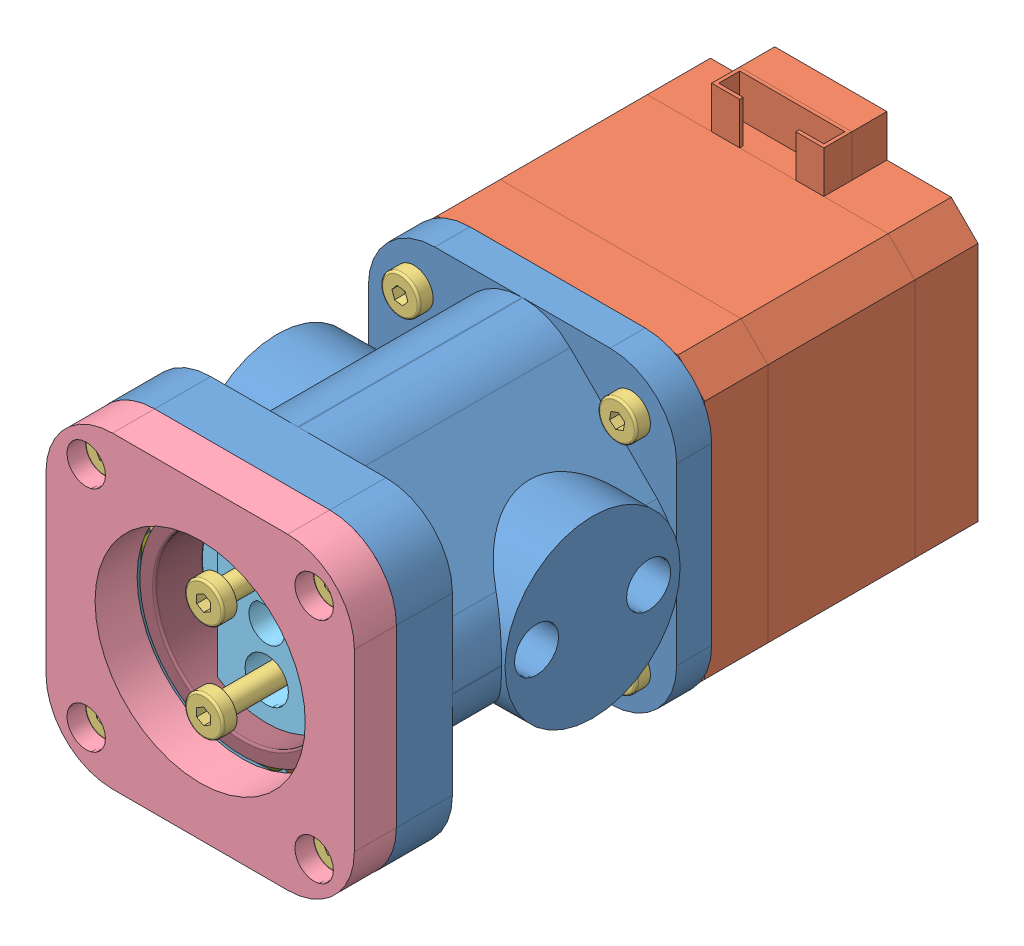
SolidWorks assembly Gelenk_4, configuration Standard. Lengths in mm.
Overall size (52.01 53.01 90).
42 component instances, 32 part files, 18 mates.
Components (placement in the parent):
- Gelenk_4_Frame-1: Gelenk_4_Frame [Standard] at origin size (45 44 45)
- motor-1: motor [Default] at (0 0 -56.5) x (0 1 0) z (1 0 0) size (48 63 42)
- socket head thin cap screw_din-1: socket head thin cap screw_din [DIN 7984 - M3 x 8 --- 6.5N] at (-15.5 15.5 -10.5) x (0 0 -1) z (0.93736 0.348363 0) size (10 5.5 5.5)
- Gelenk_4_Case-2: Gelenk_4_Case [Standard] at (0 0 27.5) size (44 44 6)
- Gelenk_4_Kupplung_Motor-1: Gelenk_4_Kupplung_Motor [Standard] at (0 0 -8.5) x (0 1 0) z (0 0 1) size (30 30 32.5)
- socket head thin cap screw_din-5: socket head thin cap screw_din [DIN 7984 - M3 x 8 --- 6.5N] at (15.5 15.5 -10.5) x (0 0 -1) z (0.348363 -0.93736 0) size (10 5.5 5.5)
- socket head thin cap screw_din-6: socket head thin cap screw_din [DIN 7984 - M3 x 8 --- 6.5N] at (15.5 -15.5 -10.5) x (0 0 -1) z (-0.93736 -0.348363 0) size (10 5.5 5.5)
- socket head thin cap screw_din-7: socket head thin cap screw_din [DIN 7984 - M3 x 8 --- 6.5N] at (-15.5 -15.5 -10.5) x (0 0 -1) z (-0.348363 0.93736 0) size (10 5.5 5.5)
- 06153436-1: 06153436 [Default] at (0 0 27.5) x (0.779979 -0.625805 0) z (-0.625805 -0.779979 0) size (37 7 37)
  - 06153436_01-1: 06153436_01 [Default] at origin size (3.6 3.6 3.6)
  - 06153436_02-1: 06153436_02 [Default] at origin size (3.6 3.6 3.6)
  - 06153436_03-1: 06153436_03 [Default] at origin size (3.6 3.6 3.6)
  - 06153436_04-1: 06153436_04 [Default] at origin size (3.6 3.6 3.6)
  - 06153436_05-1: 06153436_05 [Default] at origin size (3.6 3.6 3.6)
  - 06153436_06-1: 06153436_06 [Default] at origin size (3.6 3.6 3.6)
  - 06153436_07-1: 06153436_07 [Default] at origin size (3.6 3.6 3.6)
  - 06153436_08-1: 06153436_08 [Default] at origin size (3.6 3.6 3.6)
  - 06153436_09-1: 06153436_09 [Default] at origin size (3.6 3.6 3.6)
  - 06153436_10-1: 06153436_10 [Default] at origin size (3.6 3.6 3.6)
  - 06153436_11-1: 06153436_11 [Default] at origin size (3.6 3.6 3.6)
  - 06153436_12-1: 06153436_12 [Default] at origin size (3.6 3.6 3.6)
  - 06153436_13-1: 06153436_13 [Default] at origin size (3.6 3.6 3.6)
  - 06153436_14-1: 06153436_14 [Default] at origin size (3.6 3.6 3.6)
  - 06153436_15-1: 06153436_15 [Default] at origin size (3.6 3.6 3.6)
  - 06153436_16-1: 06153436_16 [Default] at origin size (3.6 3.6 3.6)
  - 06153436_17-1: 06153436_17 [Default] at origin size (3.6 3.6 3.6)
  - 06153436_18-1: 06153436_18 [Default] at origin size (3.6 3.6 3.6)
  - 06153436_19-1: 06153436_19 [Default] at origin size (3.6 3.6 3.6)
  - 06153436_20-1: 06153436_20 [Default] at origin size (3.6 3.6 3.6)
  - 06153436_21-1: 06153436_21 [Default] at origin size (3.6 3.6 3.6)
  - 06153436_22-1: 06153436_22 [Default] at origin size (3.6 3.6 3.6)
  - 06153436_23-1: 06153436_23 [Default] at origin size (3.6 3.6 3.6)
  - 06153436_24-1: 06153436_24 [Default] at origin size (3.6 3.6 3.6)
  - 06153436_25-1: 06153436_25 [Default] at origin size (3.6 3.6 3.6)
  - 06153436_26-1: 06153436_26 [Default] at origin size (29.2 7 29.2)
  - 06153436_27-1: 06153436_27 [Default] at origin size (37 7 37)
- socket head thin cap screw_din-8: socket head thin cap screw_din [DIN 7984 - M3 x 10 --- 8.5N] at (16.2635 16.2635 31) x (0 0 -1) z (1 0 0) size (12 5.5 5.5)
- socket head thin cap screw_din-9: socket head thin cap screw_din [DIN 7984 - M3 x 10 --- 8.5N] at (16.2635 -16.2635 31) x (0 0 -1) z (0 -1 0) size (12 5.5 5.5)
- socket head thin cap screw_din-10: socket head thin cap screw_din [DIN 7984 - M3 x 10 --- 8.5N] at (-16.2635 -16.2635 31) x (0 0 -1) z (-1 0 0) size (12 5.5 5.5)
- socket head thin cap screw_din-11: socket head thin cap screw_din [DIN 7984 - M3 x 10 --- 8.5N] at (-16.2635 16.2635 31) x (0 0 -1) z (0 1 0) size (12 5.5 5.5)
- socket head thin cap screw_din-13: socket head thin cap screw_din [DIN 7984 - M3 x 16 --- 14.5N] at (0 7 33) x (0 0 -1) z (1 0 0) size (18 5.5 5.5)
- socket head thin cap screw_din-14: socket head thin cap screw_din [DIN 7984 - M3 x 16 --- 14.5N] at (0 -7 33) x (0 0 -1) z (1 0 0) size (18 5.5 5.5)
Mates (geometry in assembly coordinates):
- Deckungsgleich3: coincident aligned: plane of Gelenk_4_Frame-1 through (0 0 0) normal (0 0 1)
- Deckungsgleich4: coincident aligned: plane of Gelenk_4_Frame-1 through (0 0 0) normal (0 1 0)
- Deckungsgleich5: coincident aligned: plane of Gelenk_4_Frame-1 through (0 0 0) normal (1 0 0)
- Deckungsgleich6: coincident aligned: plane of Gelenk_4_Frame-1 through (0 0 0) normal (0 1 0); plane of Gelenk_4_Case-2 through (0 0 27.5) normal (0 1 0)
- Deckungsgleich7: coincident aligned: plane of Gelenk_4_Frame-1 through (0 0 0) normal (1 0 0); plane of Gelenk_4_Case-2 through (0 0 27.5) normal (1 0 0)
- Konzentrisch6: concentric aligned: cylinder of Gelenk_4_Kupplung_Motor-1 through (0 0 -8.5) axis (0 0 -1) radius 7.5; cylinder of motor-1 through (0 0 -15.5) axis (0 0 -1) radius 11
- Parallel2: parallel anti-aligned: plane of motor-1 through (-1.5 2 -8.5) normal (0 1 0); plane of Gelenk_4_Kupplung_Motor-1 through (-1.3711 2.15 24) normal (0 -1 0)
- Deckungsgleich13: coincident anti-aligned: plane of motor-1 through (0 3 -8.5) normal (0 0 1); plane of Gelenk_4_Kupplung_Motor-1 through (0 0 -8.5) normal (0 0 -1)
- Deckungsgleich201: coincident aligned: plane of motor-1 through (0 0 -56.5) normal (0 1 0)
- Deckungsgleich211: coincident aligned: plane of motor-1 through (0 0 -56.5) normal (1 0 0)
- Deckungsgleich22: coincident anti-aligned: plane of Gelenk_4_Frame-1 through (0 0 -17.5) normal (0 0 -1); plane of motor-1 through (0 0 -17.5) normal (0 0 1)
- Konzentrisch123: concentric aligned: cylinder of Gelenk_4_Frame-1 through (-15.5 15.5 -17.5) axis (0 0 1) radius 1.75; cylinder of socket head thin cap screw_din-1 through (-15.5 15.5 21.25) axis (0 0 1) radius 1.5
- Deckungsgleich213: coincident anti-aligned: plane of Gelenk_4_Frame-1 through (0 0 -12.5) normal (0 0 1); plane of socket head thin cap screw_din-1 through (-16.458 18.0777 -12.5) normal (0 0 -1)
- Deckungsgleich214: coincident anti-aligned: plane of Gelenk_4_Frame-1 through (-12.5 0.065 27.5) normal (0 0 1); plane of Gelenk_4_Case-2 through (-12.5 12.5 27.5) normal (0 0 -1)
- Konzentrisch124: concentric aligned: cylinder of Gelenk_4_Frame-1 through (0 0 20.5) axis (0 0 1) radius 18.65; cylinder of 06153436-1/06153436_27-1 through (0 0 24) axis (0 0 1) radius 18.5
- Deckungsgleich215: coincident anti-aligned: plane of Gelenk_4_Frame-1 through (0 0 20.5) normal (0 0 1); plane of 06153436-1/06153436_27-1 through (-10.8264 -13.4936 20.5) normal (0 0 -1)
- Konzentrisch130: concentric anti-aligned: cylinder of Gelenk_4_Case-2 through (16.2635 16.2635 33.5) axis (0 0 -1) radius 1.75; cylinder of socket head thin cap screw_din-8 through (16.2635 16.2635 62.75) axis (0 0 1) radius 2.75
- Deckungsgleich226: coincident anti-aligned: plane of Gelenk_4_Case-2 through (16.2635 16.2635 29) normal (0 0 1); plane of socket head thin cap screw_din-8 through (16.2635 19.0135 29) normal (0 0 -1)
